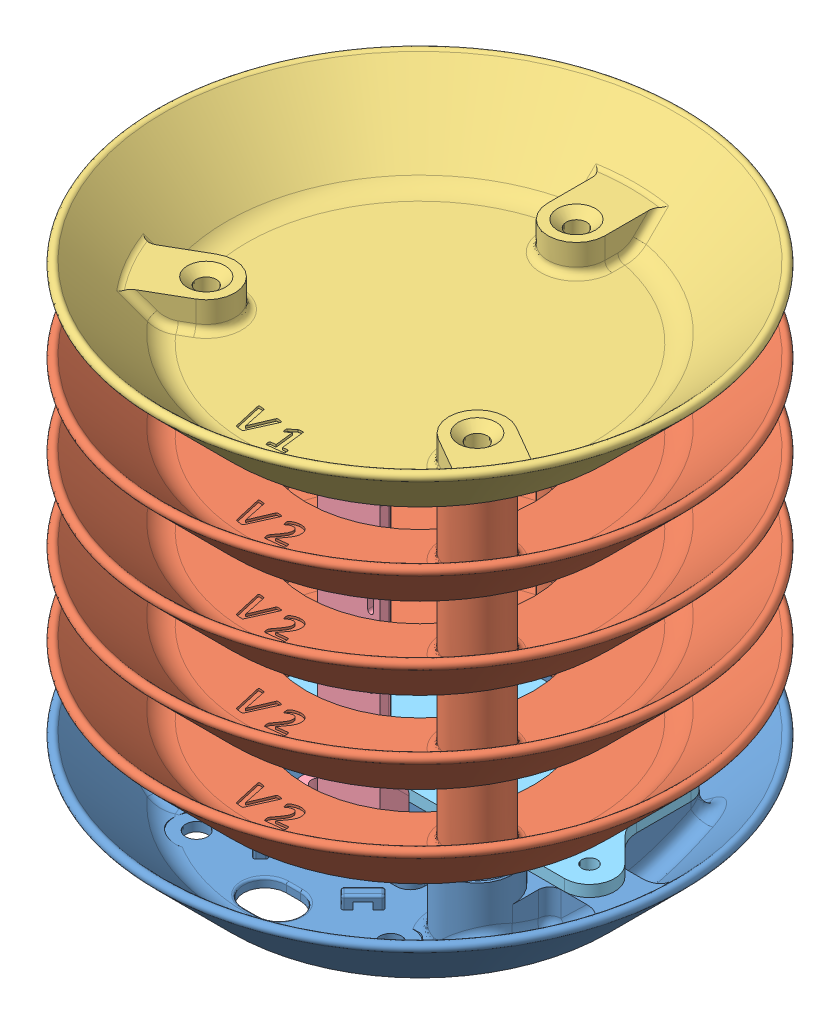
SolidWorks assembly Weather Station Assy, QT Py, configuration Default. Lengths in mm.
Overall size (118.64 109.68 118.64).
9 component instances, 6 part files, 24 mates.
Components (placement in the parent):
- Base, QT Py ESP32 - Weather Station-1: Base, QT Py ESP32 - Weather Station [Default] at origin size (118.64 20.11 118.64)
- Fin - Weather Station-1: Fin - Weather Station [Default] at (0 18.2083 0) size (118.64 20.11 118.64)
- Fin - Weather Station-2: Fin - Weather Station [Default] at (0 36.4166 0) size (118.64 20.11 118.64)
- Fin - Weather Station-3: Fin - Weather Station [Default] at (0 54.625 0) size (118.64 20.11 118.64)
- Fin - Weather Station-4: Fin - Weather Station [Default] at (0 72.8333 0) size (118.64 20.11 118.64)
- Cap - Weather Station-1: Cap - Weather Station [Default] at (0 91.0416 0) size (118.64 18.64 118.64)
- Sensor Holder, Sparkfun BME280 - Weather Station -1: Sensor Holder, Sparkfun BME280 - Weather Station  [Default] at (0 2.032 12.954) size (27.53 76.71 6.53)
- CPU Cover, QT Py ESP32 - Weather Station-1: CPU Cover, QT Py ESP32 - Weather Station [Default] at (0 12.192 -8.89) size (93.98 8.45 44.8)
- CPU Holder, QT Py - Weather Station-1: CPU Holder, QT Py - Weather Station [Default] at (-3.1115 10.541 -9.4615) x (1 0 0) z (0 0 -1) size (25.91 4.95 30.86)
Mates (geometry in assembly coordinates):
- Concentric1: concentric aligned: cylinder of Base, QT Py ESP32 - Weather Station-1 through (30.2459 40.423 17.4625) axis (0 -1 0) radius 7.8541; cylinder of Mid-1 through (30.2459 54.3771 17.4625) axis (0 -1 0) radius 6.35
- Concentric2: concentric aligned: cylinder of Base, QT Py ESP32 - Weather Station-1 through (-30.2459 40.423 17.4625) axis (0 -1 0) radius 7.8541; cylinder of Mid-1 through (-30.2459 54.3771 17.4625) axis (0 -1 0) radius 6.35
- Coincident1: coincident anti-aligned: plane of Base, QT Py ESP32 - Weather Station-1 through (-60.325 18.2083 0) normal (0 1 0); plane of Mid-1 through (0 18.2083 0) normal (0 -1 0)
- Concentric3: concentric aligned: cylinder of Mid-1 through (0 54.3771 -34.925) axis (0 -1 0) radius 6.35; cylinder of Mid-2 through (0 72.5855 -34.925) axis (0 -1 0) radius 6.35
- Concentric4: concentric aligned: cylinder of Mid-1 through (-30.2459 54.3771 17.4625) axis (0 -1 0) radius 6.35; cylinder of Mid-2 through (-30.2459 72.5855 17.4625) axis (0 -1 0) radius 6.35
- Coincident2: coincident anti-aligned: plane of Mid-1 through (-60.325 36.4166 0) normal (0 1 0); plane of Mid-2 through (0 36.4166 0) normal (0 -1 0)
- Concentric5: concentric aligned: cylinder of Mid-2 through (0 72.5855 -34.925) axis (0 -1 0) radius 6.35; cylinder of Mid-3 through (0 90.7938 -34.925) axis (0 -1 0) radius 6.35
- Concentric6: concentric aligned: cylinder of Mid-2 through (-30.2459 72.5855 17.4625) axis (0 -1 0) radius 6.35; cylinder of Mid-3 through (-30.2459 90.7938 17.4625) axis (0 -1 0) radius 6.35
- Coincident3: coincident anti-aligned: plane of Mid-2 through (-60.325 54.625 0) normal (0 1 0); plane of Mid-3 through (0 54.625 0) normal (0 -1 0)
- Concentric7: concentric aligned: cylinder of Mid-3 through (0 90.7938 -34.925) axis (0 -1 0) radius 6.35; cylinder of Mid-4 through (0 109.0021 -34.925) axis (0 -1 0) radius 6.35
- Concentric8: concentric aligned: cylinder of Mid-3 through (-30.2459 90.7938 17.4625) axis (0 -1 0) radius 6.35; cylinder of Mid-4 through (-30.2459 109.0021 17.4625) axis (0 -1 0) radius 6.35
- Coincident4: coincident anti-aligned: plane of Mid-3 through (-60.325 72.8333 0) normal (0 1 0); plane of Mid-4 through (0 72.8333 0) normal (0 -1 0)
- Concentric9: concentric aligned: cylinder of Mid-4 through (0 109.0021 -34.925) axis (0 -1 0) radius 6.35; cylinder of Bottom-1 through (0 99.4236 -34.925) axis (0 -1 0) radius 6.35
- Concentric10: concentric aligned: cylinder of Mid-4 through (-30.2459 109.0021 17.4625) axis (0 -1 0) radius 6.35; cylinder of Bottom-1 through (-30.2459 99.4236 17.4625) axis (0 -1 0) radius 6.35
- Coincident5: coincident anti-aligned: plane of Mid-4 through (-60.325 91.0416 0) normal (0 1 0); plane of Bottom-1 through (0 91.0416 0) normal (0 -1 0)
- Coincident13: coincident anti-aligned: plane of Base, QT Py ESP32 - Weather Station-1 through (-41.275 2.032 0) normal (0 1 0); plane of Sensor Holder, Adafruit BME688 - Weather Station -1 through (0 2.032 12.954) normal (0 -1 0)
- Concentric16: concentric anti-aligned: cylinder of Base, QT Py ESP32 - Weather Station-1 through (-10.16 5.461 12.319) axis (0 -1 0) radius 1.7145; cylinder of Sensor Holder, Adafruit BME688 - Weather Station -1 through (-10.16 12.192 12.319) axis (0 1 0) radius 1.7272
- Concentric17: concentric anti-aligned: cylinder of Base, QT Py ESP32 - Weather Station-1 through (10.16 5.461 12.319) axis (0 -1 0) radius 1.7145; cylinder of Sensor Holder, Adafruit BME688 - Weather Station -1 through (10.16 12.192 12.319) axis (0 1 0) radius 1.7272
- Coincident14: coincident anti-aligned: plane of Base, QT Py ESP32 - Weather Station-1 through (33.528 12.192 -22.352) normal (0 1 0); plane of CPU Cover, QT Py ESP32 - Weather Station-1 through (-41.402 12.192 3.556) normal (0 -1 0)
- Concentric18: concentric aligned: cylinder of Base, QT Py ESP32 - Weather Station-1 through (13.4366 -0.002 -30.099) axis (0 1 0) radius 1.7145; cylinder of CPU Cover, QT Py ESP32 - Weather Station-1 through (13.4366 12.192 -30.099) axis (0 1 0) radius 1.7145
- Parallel2: parallel aligned: plane of Base, QT Py ESP32 - Weather Station-1 through (38.1 -0.002 9.144) normal (0 0 1); plane of CPU Cover, QT Py ESP32 - Weather Station-1 through (38.1 14.732 9.144) normal (0 0 1)
- Concentric19: concentric aligned: cylinder of Base, QT Py ESP32 - Weather Station-1 through (-3.1115 -3.5921 -22.352) axis (0 1 0) radius 1.27; cylinder of CPU Holder, QT Py - Weather Station-1 through (-3.1115 5.588 -22.352) axis (0 1 0) radius 1.27
- Parallel4: parallel aligned: plane of Base, QT Py ESP32 - Weather Station-1 through (10.033 5.588 -21.082) normal (1 0 0); plane of CPU Holder, QT Py - Weather Station-1 through (9.8425 8.9535 -18.3515) normal (1 0 0)
- Coincident16: coincident anti-aligned: plane of Base, QT Py ESP32 - Weather Station-1 through (0 5.588 0) normal (0 1 0); plane of CPU Holder, QT Py - Weather Station-1 through (-3.1115 5.588 3.429) normal (0 -1 0)
